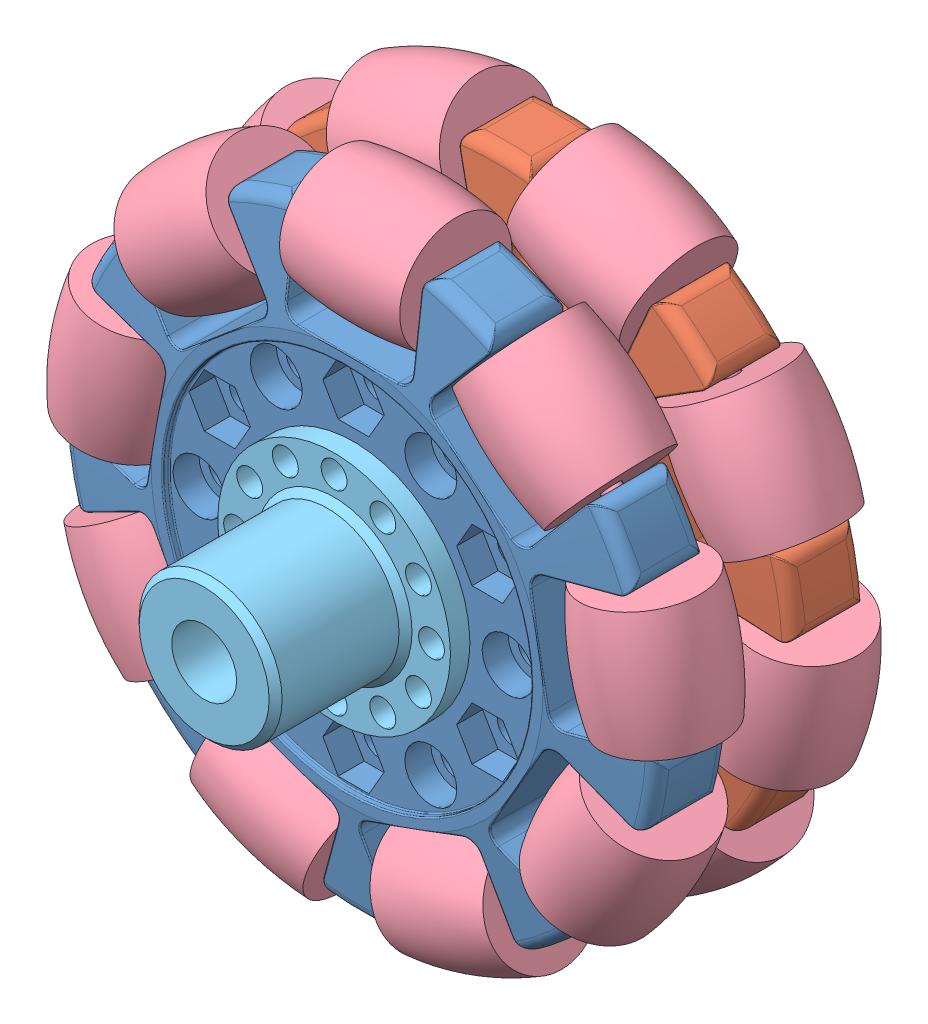
SolidWorks assembly banhxe, configuration Default. Lengths in mm.
Overall size (78.48 78.79 39.49).
22 component instances, 5 part files, 22 mates.
Components (placement in the parent):
- omniwheel_1-1: omniwheel_1 [Default] at (-17.0114 53.5739 73.2518) size (57.99 57.14 9.51)
- omniwheel_2-1: omniwheel_2 [Default] at (-17.0114 53.5739 50.5561) x (-0.5 -0.866025 0) z (0 0 -1) size (57.99 57.14 9.51)
- Part1^banhxe-1: Part1^banhxe [Default] at (-17.0114 53.5739 64.4257) x (-1 0 0) z (0 0 -1) size (35.81 35.81 11.35) (virtual)
- roller-1: roller [Default] at (-17.0114 102.7052 78.2713) x (1 0 0) z (0 0.381776 -0.924255) size (15.19 11.98 11.98)
- roller-3: roller [Default] at (14.5695 91.2107 78.2713) x (0.766044 -0.642788 0) z (0.245401 0.292458 -0.924255) size (15.19 11.98 11.98)
- roller-4: roller [Default] at (31.3734 62.1055 78.2713) x (0.173648 -0.984808 0) z (0.375976 0.066295 -0.924255) size (15.19 11.98 11.98)
- roller-5: roller [Default] at (25.5375 29.0083 78.2713) x (-0.5 -0.866025 0) z (0.330628 -0.190888 -0.924255) size (15.19 11.98 11.98)
- roller-6: roller [Default] at (-0.2076 7.4057 78.2713) x (-0.939693 -0.34202 0) z (0.130575 -0.358753 -0.924255) size (15.19 11.98 11.98)
- roller-7: roller [Default] at (-33.8153 7.4057 78.2713) x (-0.939693 0.34202 0) z (-0.130575 -0.358753 -0.924255) size (15.19 11.98 11.98)
- roller-8: roller [Default] at (-59.5603 29.0083 78.2713) x (-0.5 0.866025 0) z (-0.330628 -0.190888 -0.924255) size (15.19 11.98 11.98)
- roller-9: roller [Default] at (-65.3963 62.1055 78.2713) x (0.173648 0.984808 0) z (-0.375976 0.066295 -0.924255) size (15.19 11.98 11.98)
- roller-10: roller [Default] at (-48.5924 91.2107 78.2713) x (0.766044 0.642788 0) z (-0.245401 0.292458 -0.924255) size (15.19 11.98 11.98)
- roller-11: roller [Default] at (-18.2948 54.3149 46.7124) x (0.5 0.866025 0) z (0.290749 -0.167864 0.941959) size (15.19 11.98 11.98)
- roller-12: roller [Default] at (-18.4709 53.3166 46.7124) x (-0.173648 0.984808 0) z (0.330628 0.058299 0.941959) size (15.19 11.98 11.98)
- roller-13: roller [Default] at (-17.964 52.4387 46.7124) x (-0.766044 0.642788 0) z (0.215802 0.257183 0.941959) size (15.19 11.98 11.98)
- roller-14: roller [Default] at (-17.0114 52.092 46.7124) x (-1 0 0) z (0 0.335728 0.941959) size (15.19 11.98 11.98)
- roller-15: roller [Default] at (-16.0589 52.4387 46.7124) x (-0.766044 -0.642788 0) z (-0.215802 0.257183 0.941959) size (15.19 11.98 11.98)
- roller-16: roller [Default] at (-15.552 53.3166 46.7124) x (-0.173648 -0.984808 0) z (-0.330628 0.058299 0.941959) size (15.19 11.98 11.98)
- roller-17: roller [Default] at (-15.728 54.3149 46.7124) x (0.5 -0.866025 0) z (-0.290749 -0.167864 0.941959) size (15.19 11.98 11.98)
- roller-18: roller [Default] at (-16.5046 54.9665 46.7124) x (0.939693 -0.34202 0) z (-0.114826 -0.315481 0.941959) size (15.19 11.98 11.98)
- roller-19: roller [Default] at (-17.5183 54.9665 46.7124) x (0.939693 0.34202 0) z (0.114826 -0.315481 0.941959) size (15.19 11.98 11.98)
- Part3^banhxe-1: Part3^banhxe [Default] at (-17.0114 53.5739 72.6214) size (22.58 22.58 14.5)
Mates (geometry in assembly coordinates):
- Concentric1: concentric: cylinder of omniwheel_1-1 through (-17.0114 53.5739 68.5235) axis (0 0 1) radius 8.8261; cylinder of omniwheel_2-1 through (-17.0114 53.5739 55.2844) axis (0 0 -1) radius 8.8261
- Concentric2: concentric: circle of omniwheel_1-1; circle of omniwheel_2-1
- InPlace1: in place: plane of omniwheel_1-1 through (-17.0114 47.6916 59.2518) normal (0 0 -1); plane of ? through (0 0 59.2518) normal (0 0 -1); moOrthogonalPlaneRef_w of omniwheel_1-1 through (-17.0114 47.6916 59.2518) normal (0 0 -1); unknown of ?; plane of omniwheel_1-1 through (-17.0114 47.6916 59.2518) normal (0 0 -1); plane of ? through (0 0 59.2518) normal (-1 0 0); plane of omniwheel_1-1 through (-17.0114 49.8655 64.4257) normal (0 0 -1); unknown of Part1^banhxe-1
- Coincident1: coincident: plane of omniwheel_1-1; plane of Part1^banhxe-1
- Coincident2: coincident: moOrthogonalPlaneRef_w of omniwheel_1-1 through (-17.0114 53.5739 64.4257) normal (0 1 0); plane of Part1^banhxe-1 through (-17.0114 53.5739 64.4257) normal (0 1 0)
- Coincident3: coincident: moOrthogonalPlaneRef_w of omniwheel_1-1 through (-17.0114 53.5739 64.4257) normal (1 0 0); plane of Part1^banhxe-1 through (-17.0114 53.5739 64.4257) normal (-1 0 0)
- Concentric3: concentric: cylinder of omniwheel_1-1 through (-10.8647 79.1065 68.5235) axis (-1 0 0) radius 0.9457; cylinder of roller-1 through (-22.843 79.1065 68.5235) axis (-1 0 0) radius 0.8826
- Width1: width: plane of omniwheel_1-1 through (-23.1582 49.8655 68.5235) normal (1 0 0); plane of omniwheel_1-1 through (-10.8647 49.8655 68.5235) normal (-1 0 0); plane of roller-1 through (-22.843 74.074 66.4448) normal (-1 0 0); plane of roller-1 through (-11.1799 74.074 66.4448) normal (1 0 0)
- Concentric4: concentric: cylinder of omniwheel_2-1 through (-36.05 71.6635 55.2844) axis (-0.5 -0.866025 0) radius 0.9457; cylinder of roller-11 through (-42.0391 61.29 55.2844) axis (-0.5 -0.866025 0) radius 0.8826
- Width2: width: plane of omniwheel_2-1 through (-16.8732 46.3965 55.2844) normal (0.5 0.866025 0); plane of omniwheel_2-1 through (-10.7265 57.0429 55.2844) normal (-0.5 -0.866025 0); plane of roller-11 through (-46.4809 63.8545 57.1125) normal (-0.5 -0.866025 0); plane of roller-11 through (-40.6494 73.955 57.1125) normal (0.5 0.866025 0)
- Coincident5: coincident: plane of omniwheel_2-1 through (-13.7998 51.7197 59.3822) normal (0 0 1); plane of Part1^banhxe-1 through (-17.0114 53.5739 59.3822) normal (0 0 -1)
- InPlace2: in place: plane of omniwheel_1-1 through (-17.0114 47.6916 72.2518) normal (0 0 1); plane of ? through (0 0 72.2518) normal (0 0 1); plane of omniwheel_1-1 through (-17.0114 47.6916 72.2518) normal (0 0 1); plane of ? through (0 0 72.2518) normal (0 1 0); plane of omniwheel_1-1 through (-17.0114 47.6916 72.2518) normal (0 0 1); plane of ? through (0 0 72.2518) normal (1 0 0); plane of omniwheel_1-1 through (-17.0114 49.8655 72.6214) normal (0 0 1); unknown of Part3^banhxe-1
- Coincident6: coincident: plane of omniwheel_1-1; plane of Part3^banhxe-1
- Coincident7: coincident: moOrthogonalPlaneRef_w of omniwheel_1-1 through (-17.0114 53.5739 72.6214) normal (0 1 0); plane of Part3^banhxe-1 through (-17.0114 53.5739 72.6214) normal (0 1 0)
- Coincident8: coincident: moOrthogonalPlaneRef_w of omniwheel_1-1 through (-17.0114 53.5739 72.6214) normal (-1 0 0); plane of Part3^banhxe-1 through (-17.0114 53.5739 72.6214) normal (1 0 0)
- Concentric6: concentric: cylinder of Part3^banhxe-1 through (-25.2034 58.3036 72.6214) axis (0 0 1) radius 1.2609; cylinder of ? through (-25.2034 58.3036 111.2627) axis (0 0 1) radius 4.25
- Coincident7: coincident: plane of Part3^banhxe-1 through (-17.0114 53.5739 74.5127) normal (0 0 1); plane of ? through (-27.3409 54.6302 74.5127) normal (0 0 -1)
- Concentric7: concentric: cylinder of omniwheel_2-1 through (-30.0056 61.0761 50.7518) axis (0 0 -1) radius 1.5761; cylinder of ? through (-30.0056 61.0761 70.1893) axis (0 0 -1) radius 2.5
- Coincident9: coincident: plane of omniwheel_2-1 through (-28.5133 63.6609 50.7518) normal (0 0 -1); plane of ? through (-34.6244 61.0761 50.7518) normal (0 0 1)
- Parallel2: parallel: plane of omniwheel_2-1 through (-32.9902 61.0761 50.7518) normal (0.866025 -0.5 0); plane of ? through (-34.6244 61.0761 50.7518) normal (-0.866025 0.5 0)
- Concentric9: concentric: cylinder of Part3^banhxe-1 through (-17.0114 44.1174 82.0779) axis (0 1 0) radius 1.2609; cylinder of ? through (-17.0114 24.7315 82.0779) axis (0 -1 0) radius 1.7337
- Tangent1: tangent: cylinder of Part3^banhxe-1 through (-17.0114 53.5739 87.1214) axis (0 0 -1) radius 6.9348; plane of ? through (-18.2851 46.6392 80.9017) normal (0 1 0)
